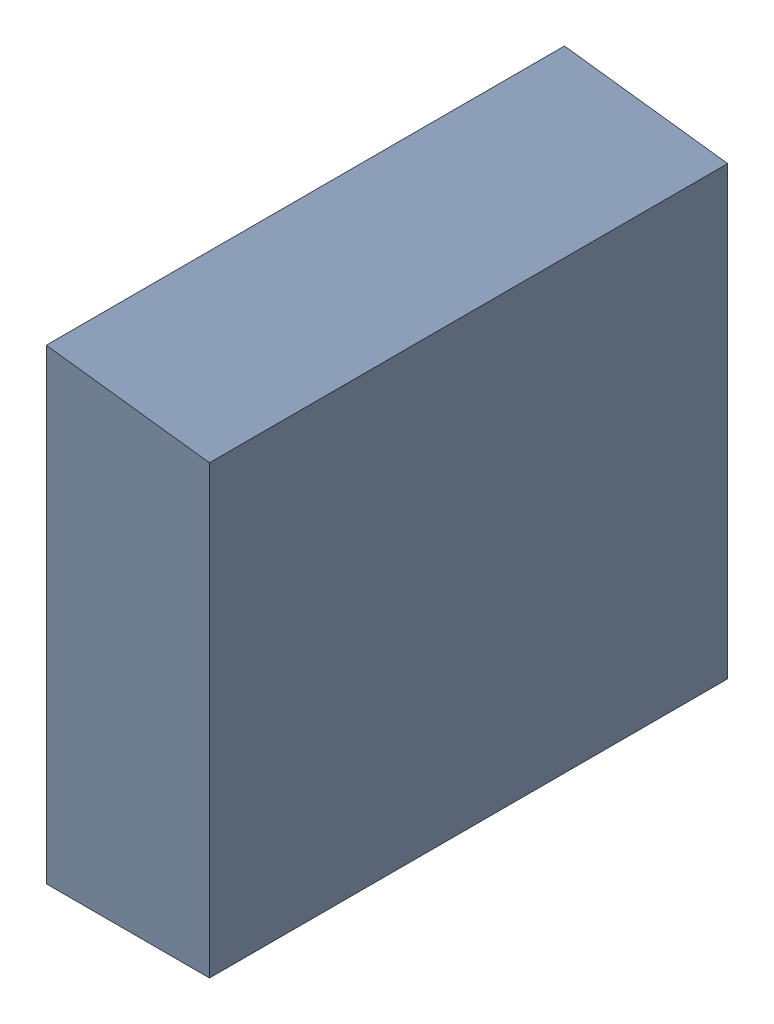
SolidWorks assembly SW3dPS-TO263-3S_BODY4, configuration Default. Lengths in mm.
Overall size (3.15 9 10).
4 component instances, 2 part files, 0 mates.
Components (placement in the parent):
- SW3dPS-TO263-3S_Free-Models8-1: SW3dPS-TO263-3S_Free-Models8 [Default] at origin size (3.15 9 10)
  - SW3dPS-TO263-3S_453496017-1: SW3dPS-TO263-3S_453496017 [Default] at (0 4.4 -4.9873) size (3.15 9 10)
    - SW3dPS-TO263-3S_Extruded18-1: SW3dPS-TO263-3S_Extruded18 [Default] at origin size (3.15 9 10)
- SW3dPS-TO263-3S_Board7-1: SW3dPS-TO263-3S_Board7 [Default] at (0 0 -0.0938) size (0.01 0.01 0.11)
